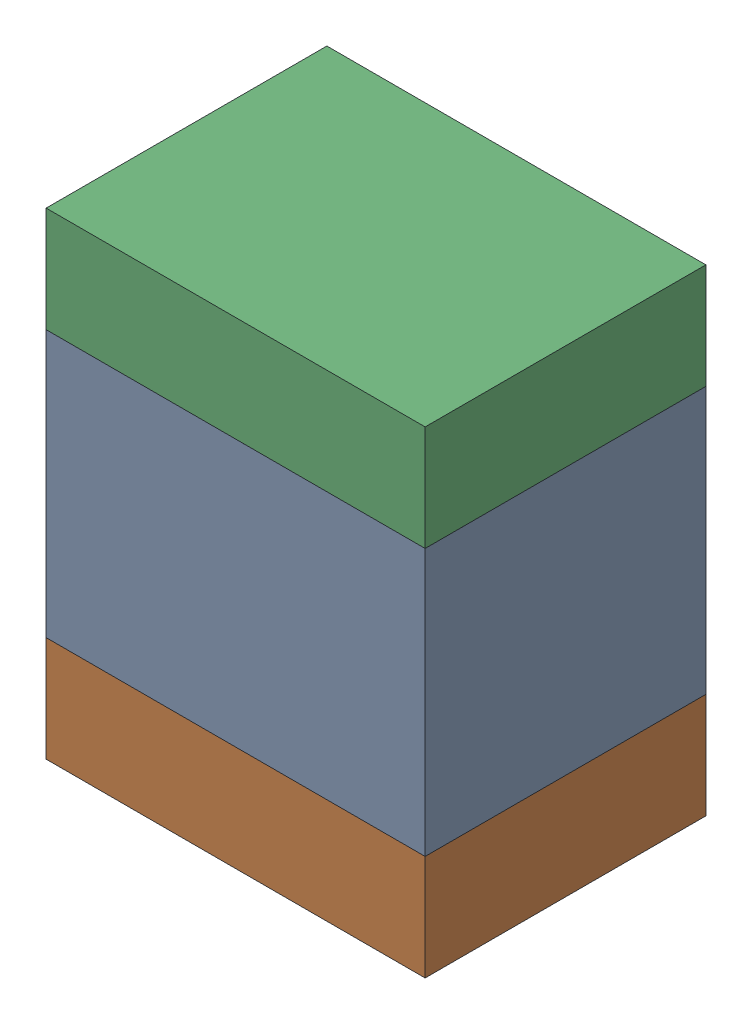
SolidWorks assembly C435PCB, configuration Default. Lengths in mm.
Overall size (2.7 3.4 2).
6 component instances, 2 part files, 0 mates.
Components (placement in the parent):
- 846487504-1: 846487504 [Default] at (87.4 78.5 -3.6638) size (2.7 1.9 2)
  - Extruded_48-1: Extruded_48 [Default] at origin size (2.7 1.9 2)
- 846487640-1: 846487640 [Default] at (87.4 77.175 -3.6638) size (2.7 0.75 2)
  - Extruded_49-1: Extruded_49 [Default] at origin size (2.7 0.75 2)
- 846487640-2: 846487640 [Default] at (87.4 79.825 -3.6638) size (2.7 0.75 2)
  - Extruded_49-1: Extruded_49 [Default] at origin size (2.7 0.75 2)
